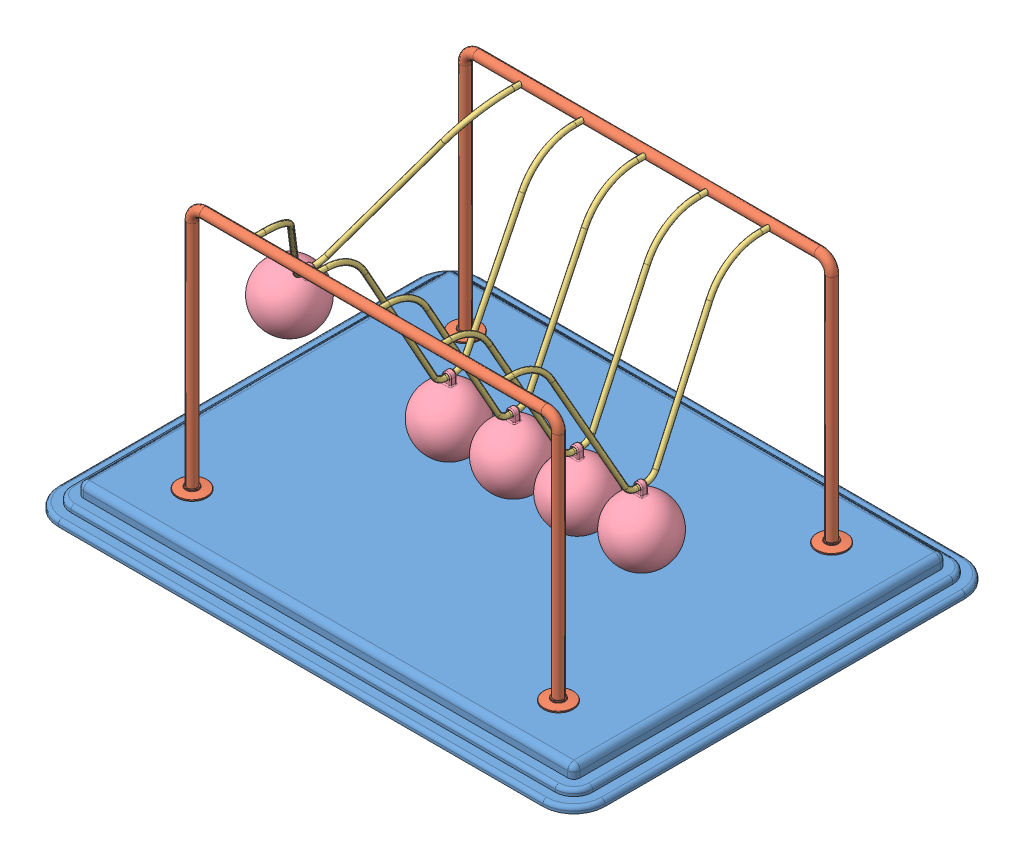
SolidWorks assembly Newtons Cradle NewtonsCradle 0235, configuration Default. Lengths in mm.
Overall size (440 222 340).
13 component instances, 4 part files, 34 mates.
Components (placement in the parent):
- Base NewtonsCradle 0235-1: Base NewtonsCradle 0235 [Default] at (-16.2968 -4.1587 11.425) size (440 20 340)
- frame NewtonsCradle 0235-1: frame NewtonsCradle 0235 [Default] at (-16.2968 144.4547 -98.575) size (319 202 24)
- frame NewtonsCradle 0235-2: frame NewtonsCradle 0235 [Default] at (-16.2968 144.4547 121.425) x (-1 0 0) z (0 0 -1) size (319 202 24)
- Hanging thing NewtonsCradle 0235-1: Hanging thing NewtonsCradle 0235 [Default] at (-157.6326 134.1825 11.425) x (0 0 1) z (-0.859985 0.510319 0) size (220 129 4)
- Hanging thing NewtonsCradle 0235-2: Hanging thing NewtonsCradle 0235 [Default] at (-66.576 122.8418 11.425) x (0 0 1) z (-0.999994 0.003446 0) size (220 129 4)
- Hanging thing NewtonsCradle 0235-3: Hanging thing NewtonsCradle 0235 [Default] at (-15.6923 122.8436 11.425) x (0 0 1) z (-0.999972 -0.007464 0) size (220 129 4)
- Hanging thing NewtonsCradle 0235-4: Hanging thing NewtonsCradle 0235 [Default] at (35.2213 122.8555 11.425) x (0 0 1) z (-0.999824 -0.018742 0) size (220 129 4)
- Hanging thing NewtonsCradle 0235-5: Hanging thing NewtonsCradle 0235 [Default] at (86.0287 122.8747 11.425) x (0 0 1) z (-0.999588 -0.028711 0) size (220 129 4)
- Sphere NewtonsCradle 0235-1: Sphere NewtonsCradle 0235 [Default] at (-195.3962 70.5436 11.425) x (0.859985 -0.510319 0) z (0 0 1) size (50 58.5 50)
- Sphere NewtonsCradle 0235-2: Sphere NewtonsCradle 0235 [Default] at (88.1533 48.9052 11.425) x (0.999588 0.028711 0) z (0 0 1) size (50 58.5 50)
- Sphere NewtonsCradle 0235-3: Sphere NewtonsCradle 0235 [Default] at (-15.14 48.8456 11.425) x (0.999972 0.007464 0) z (0 0 1) size (50 58.5 50)
- Sphere NewtonsCradle 0235-4: Sphere NewtonsCradle 0235 [Default] at (36.6081 48.8685 11.425) x (0.999824 0.018742 0) z (0 0 1) size (50 58.5 50)
- Sphere NewtonsCradle 0235-5: Sphere NewtonsCradle 0235 [Default] at (-66.831 48.8422 11.425) x (0.999994 -0.003446 0) z (0 0 1) size (50 58.5 50)
Mates (geometry in assembly coordinates):
- Coincident1: coincident anti-aligned: plane of Base-1 through (-211.2968 5.8413 156.425) normal (0 1 0); plane of frame-2 through (-175.7968 5.8413 121.425) normal (0 -1 0)
- Coincident2: coincident anti-aligned: plane of Base-1 through (-211.2968 5.8413 156.425) normal (0 1 0); plane of frame-1 through (143.2032 5.8413 -98.575) normal (0 -1 0)
- Concentric1: concentric anti-aligned: cylinder of frame-1 through (-116.2968 203.8413 -94.575) axis (0 0 -1) radius 2; cylinder of frame-2 through (-116.2968 203.8413 117.425) axis (0 0 1) radius 2
- Concentric2: concentric anti-aligned: cylinder of frame-1 through (83.7032 203.8413 -94.575) axis (0 0 -1) radius 2; cylinder of frame-2 through (83.7032 203.8413 117.425) axis (0 0 1) radius 2
- Distance1: distance = 60 mm: plane of frame-1 through (-16.2968 144.4547 -98.575) normal (0 0 1); line of Base-1 through (-211.2968 -12.1587 -158.575) axis (1 0 0)
- Distance2: distance = 60 mm: line of Base-1 through (178.7032 -12.1587 181.425) axis (-1 0 0); plane of frame-2 through (-16.2968 144.4547 121.425) normal (0 0 -1)
- Distance3: distance = 220 mm: plane of frame-2 through (-16.2968 144.4547 121.425) normal (-1 0 0); line of Base-1 through (-236.2968 -12.1587 156.425) axis (0 0 -1)
- Concentric3: concentric anti-aligned: cylinder of frame-1 through (-116.2968 203.8413 -94.575) axis (0 0 -1) radius 2; cylinder of Hanging thing-1 through (-116.2968 203.8413 111.425) axis (0 0 1) radius 2
- Concentric4: concentric anti-aligned: cylinder of frame-1 through (-116.2968 203.8413 -94.575) axis (0 0 -1) radius 2; cylinder of Hanging thing-1 through (-116.2968 203.8413 -98.575) axis (0 0 1) radius 2
- Concentric5: concentric aligned: cylinder of frame-2 through (-66.2968 203.8413 117.425) axis (0 0 1) radius 2; cylinder of Hanging thing-2 through (-66.2968 203.8413 111.425) axis (0 0 1) radius 2
- Concentric6: concentric aligned: cylinder of frame-2 through (-16.2968 203.8413 117.425) axis (0 0 1) radius 2; cylinder of Hanging thing-3 through (-16.2968 203.8413 111.425) axis (0 0 1) radius 2
- Concentric7: concentric aligned: cylinder of frame-2 through (33.7032 203.8413 117.425) axis (0 0 1) radius 2; cylinder of Hanging thing-4 through (33.7032 203.8413 111.425) axis (0 0 1) radius 2
- Concentric8: concentric aligned: cylinder of frame-2 through (83.7032 203.8413 117.425) axis (0 0 1) radius 2; cylinder of Hanging thing-5 through (83.7032 203.8413 111.425) axis (0 0 1) radius 2
- Coincident5: coincident anti-aligned: plane of frame-2 through (83.7032 203.8413 121.425) normal (0 0 -1); plane of Hanging thing-5 through (83.7032 203.8413 121.425) normal (0 0 1)
- Coincident6: coincident anti-aligned: plane of frame-2 through (33.7032 203.8413 121.425) normal (0 0 -1); plane of Hanging thing-4 through (33.7032 203.8413 121.425) normal (0 0 1)
- Coincident7: coincident anti-aligned: plane of frame-2 through (-16.2968 203.8413 121.425) normal (0 0 -1); plane of Hanging thing-3 through (-16.2968 203.8413 121.425) normal (0 0 1)
- Coincident8: coincident anti-aligned: plane of frame-2 through (-66.2968 203.8413 121.425) normal (0 0 -1); plane of Hanging thing-2 through (-66.2968 203.8413 121.425) normal (0 0 1)
- Coincident9: coincident anti-aligned: plane of frame-2 through (-116.2968 203.8413 121.425) normal (0 0 -1); plane of Hanging thing-1 through (-116.2968 203.8413 121.425) normal (0 0 1)
- Concentric9: concentric anti-aligned: cylinder of Hanging thing-1 through (-117.0163 78.8434 7.925) axis (0 0 1) radius 2; cylinder of Sphere-1 through (-117.0163 78.8434 13.925) axis (0 0 -1) radius 2
- Concentric13: concentric anti-aligned: cylinder of Hanging thing-2 through (-66.7276 78.842 7.925) axis (0 0 1) radius 2; cylinder of Sphere-5 through (-66.7276 78.842 13.925) axis (0 0 -1) radius 2
- Concentric15: concentric anti-aligned: cylinder of Hanging thing-3 through (-15.3639 78.8448 7.925) axis (0 0 1) radius 2; cylinder of Sphere-3 through (-15.3639 78.8448 13.925) axis (0 0 -1) radius 2
- Concentric16: concentric anti-aligned: cylinder of Hanging thing-5 through (87.292 78.8928 7.925) axis (0 0 1) radius 2; cylinder of Sphere-2 through (87.292 78.8928 13.925) axis (0 0 -1) radius 2
- Concentric17: concentric anti-aligned: cylinder of Hanging thing-4 through (36.0459 78.8632 7.925) axis (0 0 1) radius 2; cylinder of Sphere-4 through (36.0459 78.8632 13.925) axis (0 0 -1) radius 2
- Parallel1: parallel anti-aligned: plane of Hanging thing-1; plane of Sphere-1
- Coincident22: coincident anti-aligned: plane of Hanging thing-1; plane of Sphere-1
- Coincident12: coincident aligned: plane of Hanging thing-2 through (-66.576 122.8418 11.425) normal (0 0 1); plane of Sphere-5 through (-66.831 48.8422 11.425) normal (0 0 1)
- Coincident10: coincident aligned: plane of Hanging thing-1 through (-116.763 122.8426 11.425) normal (0 0 1); plane of Sphere-1 through (-118.5806 48.8842 11.425) normal (0 0 1)
- Coincident13: coincident anti-aligned: plane of Hanging thing-2 through (-66.576 122.8418 11.425) normal (-0.999994 0.003446 0); plane of Sphere-5 through (-66.831 48.8422 11.425) normal (0.999994 -0.003446 0)
- Coincident14: coincident anti-aligned: plane of Hanging thing-3 through (-15.6923 122.8436 11.425) normal (-0.999972 -0.007464 0); plane of Sphere-3 through (-15.14 48.8456 11.425) normal (0.999972 0.007464 0)
- Coincident15: coincident aligned: plane of Hanging thing-3 through (-15.6923 122.8436 11.425) normal (0 0 1); plane of Sphere-3 through (-15.14 48.8456 11.425) normal (0 0 1)
- Coincident18: coincident aligned: plane of Hanging thing-4 through (35.2213 122.8555 11.425) normal (0 0 1); plane of Sphere-4 through (36.6081 48.8685 11.425) normal (0 0 1)
- Coincident19: coincident anti-aligned: plane of Hanging thing-4 through (35.2213 122.8555 11.425) normal (-0.999824 -0.018742 0); plane of Sphere-4 through (36.6081 48.8685 11.425) normal (0.999824 0.018742 0)
- Coincident20: coincident anti-aligned: plane of Hanging thing-5 through (86.0287 122.8747 11.425) normal (-0.999588 -0.028711 0); plane of Sphere-2 through (88.1533 48.9052 11.425) normal (0.999588 0.028711 0)
- Coincident21: coincident aligned: plane of Hanging thing-5 through (86.0287 122.8747 11.425) normal (0 0 1); plane of Sphere-2 through (88.1533 48.9052 11.425) normal (0 0 1)
